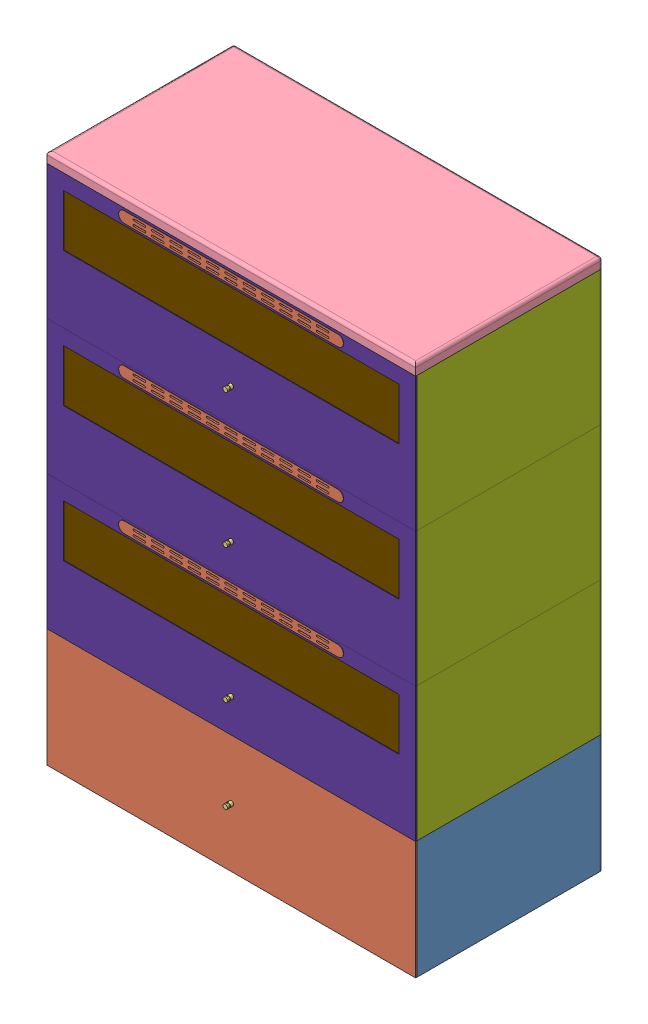
SolidWorks assembly PROTOTIPO2, configuration Default. Lengths in mm.
Overall size (1208 1761 637).
271 component instances, 22 part files, 21 mates.
Components (placement in the parent):
- A_Reservatorio-1: A_Reservatorio [Default] at (-162.7352 -41.8365 75.0131) size (1208 407 632)
  - EstruturaReservatorio-1: EstruturaReservatorio [Default] at (444.341 733.9299 556.3755) size (1208 387 608)
  - PortaReservatorio-1: PortaReservatorio [Default] at (444.341 733.9299 1164.3763) size (1208 387 608)
  - PuxadorGavetaReservatorio-1: PuxadorGavetaReservatorio [Default] at (444.341 733.9299 1188.3763) x (0.021258 -0.999774 0) z (0 0 1) size (15 15 20)
  - ApoioReservatorio-1: ApoioReservatorio [Default] at (948.341 520.4299 1084.3755) x (0.91987 0 -0.392224) z (0.392224 0 0.91987) size (50 20 50)
  - ApoioReservatorio-2: ApoioReservatorio [Default] at (-59.659 520.4299 1084.3755) x (0.91987 0 -0.392224) z (0.392224 0 0.91987) size (50 20 50)
  - ApoioReservatorio-3: ApoioReservatorio [Default] at (948.341 520.4299 636.3755) x (0.91987 0 -0.392224) z (0.392224 0 0.91987) size (50 20 50)
  - ApoioReservatorio-4: ApoioReservatorio [Default] at (-59.659 520.4299 636.3755) x (0.91987 0 -0.392224) z (0.392224 0 0.91987) size (50 20 50)
- EncaixeEntreModulos-1: EncaixeEntreModulos [Default] at (-318.3941 883.5934 1235.3886) size (12 4 12)
- EncaixeEntreModulos-2: EncaixeEntreModulos [Default] at (-318.3941 883.5934 635.3886) x (0 0 1) z (-1 0 0) size (12 4 12)
- EncaixeEntreModulos-3: EncaixeEntreModulos [Default] at (881.6059 883.5934 635.3886) x (-1 0 0) z (0 0 -1) size (12 4 12)
- EncaixeEntreModulos-4: EncaixeEntreModulos [Default] at (881.6059 883.5934 1235.3886) x (0 0 -1) z (1 0 0) size (12 4 12)
- A_Modulo-1: A_Modulo [Default] at (130.4864 669.7553 359.7584) size (1208 450 613)
  - Modulo_Peca1-1: Modulo_Peca1 [Default] at (151.1194 215.8381 575.6302) size (604 440 608)
  - Modulo_Peca2-2: Modulo_Peca2 [Default] at (151.1194 215.8381 575.6302) x (-1 0 0) z (0 0 -1) size (644 440 608)
  - Placas_divisao_modulo-3: Placas_divisao_modulo [Default] at (151.1194 278.8381 575.6302) size (1104 77 504)
  - A_Gaveta-3: A_Gaveta [Default] at (-1.3006 -541.9592 64.8858) size (1104 41 504.01)
    - Estrutura_gaveta-2: Estrutura_gaveta [Default] at (152.42 973.7974 512.7504) size (1104 4 504.01)
    - Copo_cultura-81: Copo_cultura [Default] at (-333.58 977.7974 348.7504) size (108 2 164)
    - Copo_cultura-82: Copo_cultura [Default] at (-225.58 977.7974 348.7504) size (108 2 164)
    - Copo_cultura-83: Copo_cultura [Default] at (-117.58 977.7974 348.7504) size (108 2 164)
    - Copo_cultura-84: Copo_cultura [Default] at (-9.58 977.7974 348.7504) size (108 2 164)
    - Copo_cultura-85: Copo_cultura [Default] at (98.42 977.7974 348.7504) size (108 2 164)
    - Copo_cultura-86: Copo_cultura [Default] at (206.42 977.7974 348.7504) size (108 2 164)
    - Copo_cultura-87: Copo_cultura [Default] at (314.42 977.7974 348.7504) size (108 2 164)
    - Copo_cultura-88: Copo_cultura [Default] at (422.42 977.7974 348.7504) size (108 2 164)
    - Copo_cultura-89: Copo_cultura [Default] at (530.42 977.7974 348.7504) size (108 2 164)
    - Copo_cultura-90: Copo_cultura [Default] at (638.42 977.7974 348.7504) size (108 2 164)
    - Copo_cultura-91: Copo_cultura [Default] at (-333.58 977.7974 512.7504) size (108 2 164)
    - Copo_cultura-92: Copo_cultura [Default] at (-333.58 977.7974 676.7504) size (108 2 164)
    - Copo_cultura-93: Copo_cultura [Default] at (-225.58 977.7974 512.7504) size (108 2 164)
    - Copo_cultura-94: Copo_cultura [Default] at (-225.58 977.7974 676.7504) size (108 2 164)
    - Copo_cultura-95: Copo_cultura [Default] at (-117.58 977.7974 512.7504) size (108 2 164)
    - Copo_cultura-96: Copo_cultura [Default] at (-117.58 977.7974 676.7504) size (108 2 164)
    - Copo_cultura-97: Copo_cultura [Default] at (-9.58 977.7974 512.7504) size (108 2 164)
    - Copo_cultura-98: Copo_cultura [Default] at (-9.58 977.7974 676.7504) size (108 2 164)
    - Copo_cultura-99: Copo_cultura [Default] at (98.42 977.7974 512.7504) size (108 2 164)
    - Copo_cultura-100: Copo_cultura [Default] at (98.42 977.7974 676.7504) size (108 2 164)
    - Copo_cultura-101: Copo_cultura [Default] at (206.42 977.7974 512.7504) size (108 2 164)
    - Copo_cultura-102: Copo_cultura [Default] at (206.42 977.7974 676.7504) size (108 2 164)
    - Copo_cultura-103: Copo_cultura [Default] at (314.42 977.7974 512.7504) size (108 2 164)
    - Copo_cultura-104: Copo_cultura [Default] at (314.42 977.7974 676.7504) size (108 2 164)
    - Copo_cultura-105: Copo_cultura [Default] at (422.42 977.7974 512.7504) size (108 2 164)
    - Copo_cultura-106: Copo_cultura [Default] at (422.42 977.7974 676.7504) size (108 2 164)
    - Copo_cultura-107: Copo_cultura [Default] at (530.42 977.7974 512.7504) size (108 2 164)
    - Copo_cultura-108: Copo_cultura [Default] at (530.42 977.7974 676.7504) size (108 2 164)
    - Copo_cultura-109: Copo_cultura [Default] at (638.42 977.7974 512.7504) size (108 2 164)
    - Copo_cultura-110: Copo_cultura [Default] at (638.42 977.7974 676.7504) size (108 2 164)
    - Capsula_Cultura-1: Capsula_Cultura [Default] at (-333.58 976.7974 676.7504) x (0.947711 0 -0.319129) z (0.319129 0 0.947711) size (44 41 44)
    - Capsula_Cultura-2: Capsula_Cultura [Default] at (-225.58 976.7974 676.7504) x (0.947711 0 -0.319129) z (0.319129 0 0.947711) size (44 41 44)
    - Capsula_Cultura-3: Capsula_Cultura [Default] at (-117.58 976.7974 676.7504) x (0.947711 0 -0.319129) z (0.319129 0 0.947711) size (44 41 44)
    - Capsula_Cultura-4: Capsula_Cultura [Default] at (-9.58 976.7974 676.7504) x (0.947711 0 -0.319129) z (0.319129 0 0.947711) size (44 41 44)
    - Capsula_Cultura-5: Capsula_Cultura [Default] at (98.42 976.7974 676.7504) x (0.947711 0 -0.319129) z (0.319129 0 0.947711) size (44 41 44)
    - Capsula_Cultura-6: Capsula_Cultura [Default] at (206.42 976.7974 676.7504) x (0.947711 0 -0.319129) z (0.319129 0 0.947711) size (44 41 44)
    - Capsula_Cultura-7: Capsula_Cultura [Default] at (314.42 976.7974 676.7504) x (0.947711 0 -0.319129) z (0.319129 0 0.947711) size (44 41 44)
    - Capsula_Cultura-8: Capsula_Cultura [Default] at (422.42 976.7974 676.7504) x (0.947711 0 -0.319129) z (0.319129 0 0.947711) size (44 41 44)
    - Capsula_Cultura-9: Capsula_Cultura [Default] at (530.42 976.7974 676.7504) x (0.947711 0 -0.319129) z (0.319129 0 0.947711) size (44 41 44)
    - Capsula_Cultura-10: Capsula_Cultura [Default] at (638.42 976.7974 676.7504) x (0.947711 0 -0.319129) z (0.319129 0 0.947711) size (44 41 44)
    - Capsula_Cultura-11: Capsula_Cultura [Default] at (-333.58 976.7974 512.7504) x (0.947711 0 -0.319129) z (0.319129 0 0.947711) size (44 41 44)
    - Capsula_Cultura-12: Capsula_Cultura [Default] at (-333.58 976.7974 348.7504) x (0.947711 0 -0.319129) z (0.319129 0 0.947711) size (44 41 44)
    - Capsula_Cultura-13: Capsula_Cultura [Default] at (-225.58 976.7974 512.7504) x (0.947711 0 -0.319129) z (0.319129 0 0.947711) size (44 41 44)
    - Capsula_Cultura-14: Capsula_Cultura [Default] at (-225.58 976.7974 348.7504) x (0.947711 0 -0.319129) z (0.319129 0 0.947711) size (44 41 44)
    - Capsula_Cultura-15: Capsula_Cultura [Default] at (-117.58 976.7974 512.7504) x (0.947711 0 -0.319129) z (0.319129 0 0.947711) size (44 41 44)
    - Capsula_Cultura-16: Capsula_Cultura [Default] at (-117.58 976.7974 348.7504) x (0.947711 0 -0.319129) z (0.319129 0 0.947711) size (44 41 44)
    - Capsula_Cultura-17: Capsula_Cultura [Default] at (-9.58 976.7974 512.7504) x (0.947711 0 -0.319129) z (0.319129 0 0.947711) size (44 41 44)
    - Capsula_Cultura-18: Capsula_Cultura [Default] at (-9.58 976.7974 348.7504) x (0.947711 0 -0.319129) z (0.319129 0 0.947711) size (44 41 44)
    - Capsula_Cultura-19: Capsula_Cultura [Default] at (98.42 976.7974 512.7504) x (0.947711 0 -0.319129) z (0.319129 0 0.947711) size (44 41 44)
    - Capsula_Cultura-20: Capsula_Cultura [Default] at (98.42 976.7974 348.7504) x (0.947711 0 -0.319129) z (0.319129 0 0.947711) size (44 41 44)
    - Capsula_Cultura-21: Capsula_Cultura [Default] at (206.42 976.7974 512.7504) x (0.947711 0 -0.319129) z (0.319129 0 0.947711) size (44 41 44)
    - Capsula_Cultura-22: Capsula_Cultura [Default] at (206.42 976.7974 348.7504) x (0.947711 0 -0.319129) z (0.319129 0 0.947711) size (44 41 44)
    - Capsula_Cultura-23: Capsula_Cultura [Default] at (314.42 976.7974 512.7504) x (0.947711 0 -0.319129) z (0.319129 0 0.947711) size (44 41 44)
    - Capsula_Cultura-24: Capsula_Cultura [Default] at (314.42 976.7974 348.7504) x (0.947711 0 -0.319129) z (0.319129 0 0.947711) size (44 41 44)
    - Capsula_Cultura-25: Capsula_Cultura [Default] at (422.42 976.7974 512.7504) x (0.947711 0 -0.319129) z (0.319129 0 0.947711) size (44 41 44)
    - Capsula_Cultura-26: Capsula_Cultura [Default] at (422.42 976.7974 348.7504) x (0.947711 0 -0.319129) z (0.319129 0 0.947711) size (44 41 44)
    - Capsula_Cultura-27: Capsula_Cultura [Default] at (530.42 976.7974 512.7504) x (0.947711 0 -0.319129) z (0.319129 0 0.947711) size (44 41 44)
    - Capsula_Cultura-28: Capsula_Cultura [Default] at (530.42 976.7974 348.7504) x (0.947711 0 -0.319129) z (0.319129 0 0.947711) size (44 41 44)
    - Capsula_Cultura-29: Capsula_Cultura [Default] at (638.42 976.7974 512.7504) x (0.947711 0 -0.319129) z (0.319129 0 0.947711) size (44 41 44)
    - Capsula_Cultura-30: Capsula_Cultura [Default] at (638.42 976.7974 348.7504) x (0.947711 0 -0.319129) z (0.319129 0 0.947711) size (44 41 44)
  - A_Ventilador-1: A_Ventilador [Default] at (-143.7426 484.8829 374.0047) x (-1 0 0) z (0 0 -1) size (121.7 121.7 59)
    - CasingVentilador-1: CasingVentilador [Default] at (5.1379 70.9552 107.3745) size (120 120 59)
    - LigacaoFan_Casing-1: LigacaoFan_Casing [Default] at (5.1379 70.9552 74.8745) size (96 16 5)
    - Fan-1: Fan [Default] at (5.1379 70.9552 79.8745) x (-0.915029 -0.403389 0) z (0 0 1) size (92.31 92.31 5)
  - Tubo_injeccao_agua-2: Tubo_injeccao_agua [Default] at (643.0083 300.8381 325.6302) size (818.93 24.03 249.8)
  - Tubagem_electricidade-1: Tubagem_electricidade [Default] at (-368.8806 215.8381 298.6302) size (40 450 10)
- A_Modulo-4: A_Modulo [Default] at (130.4864 1109.7553 359.7584) size (1208 450 613)
  - Modulo_Peca1-1: Modulo_Peca1 [Default] at (151.1194 215.8381 575.6302) size (604 440 608)
  - Modulo_Peca2-2: Modulo_Peca2 [Default] at (151.1194 215.8381 575.6302) x (-1 0 0) z (0 0 -1) size (644 440 608)
  - Placas_divisao_modulo-3: Placas_divisao_modulo [Default] at (151.1194 278.8381 575.6302) size (1104 77 504)
  - A_Gaveta-3: A_Gaveta [Default] at (-1.3006 -541.9592 64.8858) size (1104 41 504.01)
    - Estrutura_gaveta-2: Estrutura_gaveta [Default] at (152.42 973.7974 512.7504) size (1104 4 504.01)
    - Copo_cultura-81: Copo_cultura [Default] at (-333.58 977.7974 348.7504) size (108 2 164)
    - Copo_cultura-82: Copo_cultura [Default] at (-225.58 977.7974 348.7504) size (108 2 164)
    - Copo_cultura-83: Copo_cultura [Default] at (-117.58 977.7974 348.7504) size (108 2 164)
    - Copo_cultura-84: Copo_cultura [Default] at (-9.58 977.7974 348.7504) size (108 2 164)
    - Copo_cultura-85: Copo_cultura [Default] at (98.42 977.7974 348.7504) size (108 2 164)
    - Copo_cultura-86: Copo_cultura [Default] at (206.42 977.7974 348.7504) size (108 2 164)
    - Copo_cultura-87: Copo_cultura [Default] at (314.42 977.7974 348.7504) size (108 2 164)
    - Copo_cultura-88: Copo_cultura [Default] at (422.42 977.7974 348.7504) size (108 2 164)
    - Copo_cultura-89: Copo_cultura [Default] at (530.42 977.7974 348.7504) size (108 2 164)
    - Copo_cultura-90: Copo_cultura [Default] at (638.42 977.7974 348.7504) size (108 2 164)
    - Copo_cultura-91: Copo_cultura [Default] at (-333.58 977.7974 512.7504) size (108 2 164)
    - Copo_cultura-92: Copo_cultura [Default] at (-333.58 977.7974 676.7504) size (108 2 164)
    - Copo_cultura-93: Copo_cultura [Default] at (-225.58 977.7974 512.7504) size (108 2 164)
    - Copo_cultura-94: Copo_cultura [Default] at (-225.58 977.7974 676.7504) size (108 2 164)
    - Copo_cultura-95: Copo_cultura [Default] at (-117.58 977.7974 512.7504) size (108 2 164)
    - Copo_cultura-96: Copo_cultura [Default] at (-117.58 977.7974 676.7504) size (108 2 164)
    - Copo_cultura-97: Copo_cultura [Default] at (-9.58 977.7974 512.7504) size (108 2 164)
    - Copo_cultura-98: Copo_cultura [Default] at (-9.58 977.7974 676.7504) size (108 2 164)
    - Copo_cultura-99: Copo_cultura [Default] at (98.42 977.7974 512.7504) size (108 2 164)
    - Copo_cultura-100: Copo_cultura [Default] at (98.42 977.7974 676.7504) size (108 2 164)
    - Copo_cultura-101: Copo_cultura [Default] at (206.42 977.7974 512.7504) size (108 2 164)
    - Copo_cultura-102: Copo_cultura [Default] at (206.42 977.7974 676.7504) size (108 2 164)
    - Copo_cultura-103: Copo_cultura [Default] at (314.42 977.7974 512.7504) size (108 2 164)
    - Copo_cultura-104: Copo_cultura [Default] at (314.42 977.7974 676.7504) size (108 2 164)
    - Copo_cultura-105: Copo_cultura [Default] at (422.42 977.7974 512.7504) size (108 2 164)
    - Copo_cultura-106: Copo_cultura [Default] at (422.42 977.7974 676.7504) size (108 2 164)
    - Copo_cultura-107: Copo_cultura [Default] at (530.42 977.7974 512.7504) size (108 2 164)
    - Copo_cultura-108: Copo_cultura [Default] at (530.42 977.7974 676.7504) size (108 2 164)
    - Copo_cultura-109: Copo_cultura [Default] at (638.42 977.7974 512.7504) size (108 2 164)
    - Copo_cultura-110: Copo_cultura [Default] at (638.42 977.7974 676.7504) size (108 2 164)
    - Capsula_Cultura-1: Capsula_Cultura [Default] at (-333.58 976.7974 676.7504) x (0.947711 0 -0.319129) z (0.319129 0 0.947711) size (44 41 44)
    - Capsula_Cultura-2: Capsula_Cultura [Default] at (-225.58 976.7974 676.7504) x (0.947711 0 -0.319129) z (0.319129 0 0.947711) size (44 41 44)
    - Capsula_Cultura-3: Capsula_Cultura [Default] at (-117.58 976.7974 676.7504) x (0.947711 0 -0.319129) z (0.319129 0 0.947711) size (44 41 44)
    - Capsula_Cultura-4: Capsula_Cultura [Default] at (-9.58 976.7974 676.7504) x (0.947711 0 -0.319129) z (0.319129 0 0.947711) size (44 41 44)
    - Capsula_Cultura-5: Capsula_Cultura [Default] at (98.42 976.7974 676.7504) x (0.947711 0 -0.319129) z (0.319129 0 0.947711) size (44 41 44)
    - Capsula_Cultura-6: Capsula_Cultura [Default] at (206.42 976.7974 676.7504) x (0.947711 0 -0.319129) z (0.319129 0 0.947711) size (44 41 44)
    - Capsula_Cultura-7: Capsula_Cultura [Default] at (314.42 976.7974 676.7504) x (0.947711 0 -0.319129) z (0.319129 0 0.947711) size (44 41 44)
    - Capsula_Cultura-8: Capsula_Cultura [Default] at (422.42 976.7974 676.7504) x (0.947711 0 -0.319129) z (0.319129 0 0.947711) size (44 41 44)
    - Capsula_Cultura-9: Capsula_Cultura [Default] at (530.42 976.7974 676.7504) x (0.947711 0 -0.319129) z (0.319129 0 0.947711) size (44 41 44)
    - Capsula_Cultura-10: Capsula_Cultura [Default] at (638.42 976.7974 676.7504) x (0.947711 0 -0.319129) z (0.319129 0 0.947711) size (44 41 44)
    - Capsula_Cultura-11: Capsula_Cultura [Default] at (-333.58 976.7974 512.7504) x (0.947711 0 -0.319129) z (0.319129 0 0.947711) size (44 41 44)
    - Capsula_Cultura-12: Capsula_Cultura [Default] at (-333.58 976.7974 348.7504) x (0.947711 0 -0.319129) z (0.319129 0 0.947711) size (44 41 44)
    - Capsula_Cultura-13: Capsula_Cultura [Default] at (-225.58 976.7974 512.7504) x (0.947711 0 -0.319129) z (0.319129 0 0.947711) size (44 41 44)
    - Capsula_Cultura-14: Capsula_Cultura [Default] at (-225.58 976.7974 348.7504) x (0.947711 0 -0.319129) z (0.319129 0 0.947711) size (44 41 44)
    - Capsula_Cultura-15: Capsula_Cultura [Default] at (-117.58 976.7974 512.7504) x (0.947711 0 -0.319129) z (0.319129 0 0.947711) size (44 41 44)
    - Capsula_Cultura-16: Capsula_Cultura [Default] at (-117.58 976.7974 348.7504) x (0.947711 0 -0.319129) z (0.319129 0 0.947711) size (44 41 44)
    - Capsula_Cultura-17: Capsula_Cultura [Default] at (-9.58 976.7974 512.7504) x (0.947711 0 -0.319129) z (0.319129 0 0.947711) size (44 41 44)
    - Capsula_Cultura-18: Capsula_Cultura [Default] at (-9.58 976.7974 348.7504) x (0.947711 0 -0.319129) z (0.319129 0 0.947711) size (44 41 44)
    - Capsula_Cultura-19: Capsula_Cultura [Default] at (98.42 976.7974 512.7504) x (0.947711 0 -0.319129) z (0.319129 0 0.947711) size (44 41 44)
    - Capsula_Cultura-20: Capsula_Cultura [Default] at (98.42 976.7974 348.7504) x (0.947711 0 -0.319129) z (0.319129 0 0.947711) size (44 41 44)
    - Capsula_Cultura-21: Capsula_Cultura [Default] at (206.42 976.7974 512.7504) x (0.947711 0 -0.319129) z (0.319129 0 0.947711) size (44 41 44)
    - Capsula_Cultura-22: Capsula_Cultura [Default] at (206.42 976.7974 348.7504) x (0.947711 0 -0.319129) z (0.319129 0 0.947711) size (44 41 44)
    - Capsula_Cultura-23: Capsula_Cultura [Default] at (314.42 976.7974 512.7504) x (0.947711 0 -0.319129) z (0.319129 0 0.947711) size (44 41 44)
    - Capsula_Cultura-24: Capsula_Cultura [Default] at (314.42 976.7974 348.7504) x (0.947711 0 -0.319129) z (0.319129 0 0.947711) size (44 41 44)
    - Capsula_Cultura-25: Capsula_Cultura [Default] at (422.42 976.7974 512.7504) x (0.947711 0 -0.319129) z (0.319129 0 0.947711) size (44 41 44)
    - Capsula_Cultura-26: Capsula_Cultura [Default] at (422.42 976.7974 348.7504) x (0.947711 0 -0.319129) z (0.319129 0 0.947711) size (44 41 44)
    - Capsula_Cultura-27: Capsula_Cultura [Default] at (530.42 976.7974 512.7504) x (0.947711 0 -0.319129) z (0.319129 0 0.947711) size (44 41 44)
    - Capsula_Cultura-28: Capsula_Cultura [Default] at (530.42 976.7974 348.7504) x (0.947711 0 -0.319129) z (0.319129 0 0.947711) size (44 41 44)
    - Capsula_Cultura-29: Capsula_Cultura [Default] at (638.42 976.7974 512.7504) x (0.947711 0 -0.319129) z (0.319129 0 0.947711) size (44 41 44)
    - Capsula_Cultura-30: Capsula_Cultura [Default] at (638.42 976.7974 348.7504) x (0.947711 0 -0.319129) z (0.319129 0 0.947711) size (44 41 44)
  - A_Ventilador-1: A_Ventilador [Default] at (-143.7426 484.8829 374.0047) x (-1 0 0) z (0 0 -1) size (121.7 121.7 59)
    - CasingVentilador-1: CasingVentilador [Default] at (5.1379 70.9552 107.3745) size (120 120 59)
    - LigacaoFan_Casing-1: LigacaoFan_Casing [Default] at (5.1379 70.9552 74.8745) size (96 16 5)
    - Fan-1: Fan [Default] at (5.1379 70.9552 79.8745) x (-0.915029 -0.403389 0) z (0 0 1) size (92.31 92.31 5)
  - Tubo_injeccao_agua-2: Tubo_injeccao_agua [Default] at (643.0083 300.8381 325.6302) size (818.93 24.03 249.8)
  - Tubagem_electricidade-1: Tubagem_electricidade [Default] at (-368.8806 215.8381 298.6302) size (40 450 10)
- A_Modulo-5: A_Modulo [Default] at (130.4864 1549.7553 359.7584) size (1208 450 613)
  - Modulo_Peca1-1: Modulo_Peca1 [Default] at (151.1194 215.8381 575.6302) size (604 440 608)
  - Modulo_Peca2-2: Modulo_Peca2 [Default] at (151.1194 215.8381 575.6302) x (-1 0 0) z (0 0 -1) size (644 440 608)
  - Placas_divisao_modulo-3: Placas_divisao_modulo [Default] at (151.1194 278.8381 575.6302) size (1104 77 504)
  - A_Gaveta-3: A_Gaveta [Default] at (-1.3006 -541.9592 64.8858) size (1104 41 504.01)
    - Estrutura_gaveta-2: Estrutura_gaveta [Default] at (152.42 973.7974 512.7504) size (1104 4 504.01)
    - Copo_cultura-81: Copo_cultura [Default] at (-333.58 977.7974 348.7504) size (108 2 164)
    - Copo_cultura-82: Copo_cultura [Default] at (-225.58 977.7974 348.7504) size (108 2 164)
    - Copo_cultura-83: Copo_cultura [Default] at (-117.58 977.7974 348.7504) size (108 2 164)
    - Copo_cultura-84: Copo_cultura [Default] at (-9.58 977.7974 348.7504) size (108 2 164)
    - Copo_cultura-85: Copo_cultura [Default] at (98.42 977.7974 348.7504) size (108 2 164)
    - Copo_cultura-86: Copo_cultura [Default] at (206.42 977.7974 348.7504) size (108 2 164)
    - Copo_cultura-87: Copo_cultura [Default] at (314.42 977.7974 348.7504) size (108 2 164)
    - Copo_cultura-88: Copo_cultura [Default] at (422.42 977.7974 348.7504) size (108 2 164)
    - Copo_cultura-89: Copo_cultura [Default] at (530.42 977.7974 348.7504) size (108 2 164)
    - Copo_cultura-90: Copo_cultura [Default] at (638.42 977.7974 348.7504) size (108 2 164)
    - Copo_cultura-91: Copo_cultura [Default] at (-333.58 977.7974 512.7504) size (108 2 164)
    - Copo_cultura-92: Copo_cultura [Default] at (-333.58 977.7974 676.7504) size (108 2 164)
    - Copo_cultura-93: Copo_cultura [Default] at (-225.58 977.7974 512.7504) size (108 2 164)
    - Copo_cultura-94: Copo_cultura [Default] at (-225.58 977.7974 676.7504) size (108 2 164)
    - Copo_cultura-95: Copo_cultura [Default] at (-117.58 977.7974 512.7504) size (108 2 164)
    - Copo_cultura-96: Copo_cultura [Default] at (-117.58 977.7974 676.7504) size (108 2 164)
    - Copo_cultura-97: Copo_cultura [Default] at (-9.58 977.7974 512.7504) size (108 2 164)
    - Copo_cultura-98: Copo_cultura [Default] at (-9.58 977.7974 676.7504) size (108 2 164)
    - Copo_cultura-99: Copo_cultura [Default] at (98.42 977.7974 512.7504) size (108 2 164)
    - Copo_cultura-100: Copo_cultura [Default] at (98.42 977.7974 676.7504) size (108 2 164)
    - Copo_cultura-101: Copo_cultura [Default] at (206.42 977.7974 512.7504) size (108 2 164)
    - Copo_cultura-102: Copo_cultura [Default] at (206.42 977.7974 676.7504) size (108 2 164)
    - Copo_cultura-103: Copo_cultura [Default] at (314.42 977.7974 512.7504) size (108 2 164)
    - Copo_cultura-104: Copo_cultura [Default] at (314.42 977.7974 676.7504) size (108 2 164)
    - Copo_cultura-105: Copo_cultura [Default] at (422.42 977.7974 512.7504) size (108 2 164)
    - Copo_cultura-106: Copo_cultura [Default] at (422.42 977.7974 676.7504) size (108 2 164)
    - Copo_cultura-107: Copo_cultura [Default] at (530.42 977.7974 512.7504) size (108 2 164)
    - Copo_cultura-108: Copo_cultura [Default] at (530.42 977.7974 676.7504) size (108 2 164)
    - Copo_cultura-109: Copo_cultura [Default] at (638.42 977.7974 512.7504) size (108 2 164)
    - Copo_cultura-110: Copo_cultura [Default] at (638.42 977.7974 676.7504) size (108 2 164)
    - Capsula_Cultura-1: Capsula_Cultura [Default] at (-333.58 976.7974 676.7504) x (0.947711 0 -0.319129) z (0.319129 0 0.947711) size (44 41 44)
    - Capsula_Cultura-2: Capsula_Cultura [Default] at (-225.58 976.7974 676.7504) x (0.947711 0 -0.319129) z (0.319129 0 0.947711) size (44 41 44)
    - Capsula_Cultura-3: Capsula_Cultura [Default] at (-117.58 976.7974 676.7504) x (0.947711 0 -0.319129) z (0.319129 0 0.947711) size (44 41 44)
    - Capsula_Cultura-4: Capsula_Cultura [Default] at (-9.58 976.7974 676.7504) x (0.947711 0 -0.319129) z (0.319129 0 0.947711) size (44 41 44)
    - Capsula_Cultura-5: Capsula_Cultura [Default] at (98.42 976.7974 676.7504) x (0.947711 0 -0.319129) z (0.319129 0 0.947711) size (44 41 44)
    - Capsula_Cultura-6: Capsula_Cultura [Default] at (206.42 976.7974 676.7504) x (0.947711 0 -0.319129) z (0.319129 0 0.947711) size (44 41 44)
    - Capsula_Cultura-7: Capsula_Cultura [Default] at (314.42 976.7974 676.7504) x (0.947711 0 -0.319129) z (0.319129 0 0.947711) size (44 41 44)
    - Capsula_Cultura-8: Capsula_Cultura [Default] at (422.42 976.7974 676.7504) x (0.947711 0 -0.319129) z (0.319129 0 0.947711) size (44 41 44)
    - Capsula_Cultura-9: Capsula_Cultura [Default] at (530.42 976.7974 676.7504) x (0.947711 0 -0.319129) z (0.319129 0 0.947711) size (44 41 44)
    - Capsula_Cultura-10: Capsula_Cultura [Default] at (638.42 976.7974 676.7504) x (0.947711 0 -0.319129) z (0.319129 0 0.947711) size (44 41 44)
    - Capsula_Cultura-11: Capsula_Cultura [Default] at (-333.58 976.7974 512.7504) x (0.947711 0 -0.319129) z (0.319129 0 0.947711) size (44 41 44)
    - Capsula_Cultura-12: Capsula_Cultura [Default] at (-333.58 976.7974 348.7504) x (0.947711 0 -0.319129) z (0.319129 0 0.947711) size (44 41 44)
    - Capsula_Cultura-13: Capsula_Cultura [Default] at (-225.58 976.7974 512.7504) x (0.947711 0 -0.319129) z (0.319129 0 0.947711) size (44 41 44)
    - Capsula_Cultura-14: Capsula_Cultura [Default] at (-225.58 976.7974 348.7504) x (0.947711 0 -0.319129) z (0.319129 0 0.947711) size (44 41 44)
    - Capsula_Cultura-15: Capsula_Cultura [Default] at (-117.58 976.7974 512.7504) x (0.947711 0 -0.319129) z (0.319129 0 0.947711) size (44 41 44)
    - Capsula_Cultura-16: Capsula_Cultura [Default] at (-117.58 976.7974 348.7504) x (0.947711 0 -0.319129) z (0.319129 0 0.947711) size (44 41 44)
    - Capsula_Cultura-17: Capsula_Cultura [Default] at (-9.58 976.7974 512.7504) x (0.947711 0 -0.319129) z (0.319129 0 0.947711) size (44 41 44)
    - Capsula_Cultura-18: Capsula_Cultura [Default] at (-9.58 976.7974 348.7504) x (0.947711 0 -0.319129) z (0.319129 0 0.947711) size (44 41 44)
    - Capsula_Cultura-19: Capsula_Cultura [Default] at (98.42 976.7974 512.7504) x (0.947711 0 -0.319129) z (0.319129 0 0.947711) size (44 41 44)
    - Capsula_Cultura-20: Capsula_Cultura [Default] at (98.42 976.7974 348.7504) x (0.947711 0 -0.319129) z (0.319129 0 0.947711) size (44 41 44)
    - Capsula_Cultura-21: Capsula_Cultura [Default] at (206.42 976.7974 512.7504) x (0.947711 0 -0.319129) z (0.319129 0 0.947711) size (44 41 44)
    - Capsula_Cultura-22: Capsula_Cultura [Default] at (206.42 976.7974 348.7504) x (0.947711 0 -0.319129) z (0.319129 0 0.947711) size (44 41 44)
    - Capsula_Cultura-23: Capsula_Cultura [Default] at (314.42 976.7974 512.7504) x (0.947711 0 -0.319129) z (0.319129 0 0.947711) size (44 41 44)
    - Capsula_Cultura-24: Capsula_Cultura [Default] at (314.42 976.7974 348.7504) x (0.947711 0 -0.319129) z (0.319129 0 0.947711) size (44 41 44)
    - Capsula_Cultura-25: Capsula_Cultura [Default] at (422.42 976.7974 512.7504) x (0.947711 0 -0.319129) z (0.319129 0 0.947711) size (44 41 44)
    - Capsula_Cultura-26: Capsula_Cultura [Default] at (422.42 976.7974 348.7504) x (0.947711 0 -0.319129) z (0.319129 0 0.947711) size (44 41 44)
    - Capsula_Cultura-27: Capsula_Cultura [Default] at (530.42 976.7974 512.7504) x (0.947711 0 -0.319129) z (0.319129 0 0.947711) size (44 41 44)
    - Capsula_Cultura-28: Capsula_Cultura [Default] at (530.42 976.7974 348.7504) x (0.947711 0 -0.319129) z (0.319129 0 0.947711) size (44 41 44)
    - Capsula_Cultura-29: Capsula_Cultura [Default] at (638.42 976.7974 512.7504) x (0.947711 0 -0.319129) z (0.319129 0 0.947711) size (44 41 44)
    - Capsula_Cultura-30: Capsula_Cultura [Default] at (638.42 976.7974 348.7504) x (0.947711 0 -0.319129) z (0.319129 0 0.947711) size (44 41 44)
  - A_Ventilador-1: A_Ventilador [Default] at (-143.7426 484.8829 374.0047) x (-1 0 0) z (0 0 -1) size (121.7 121.7 59)
    - CasingVentilador-1: CasingVentilador [Default] at (5.1379 70.9552 107.3745) size (120 120 59)
    - LigacaoFan_Casing-1: LigacaoFan_Casing [Default] at (5.1379 70.9552 74.8745) size (96 16 5)
    - Fan-1: Fan [Default] at (5.1379 70.9552 79.8745) x (-0.915029 -0.403389 0) z (0 0 1) size (92.31 92.31 5)
  - Tubo_injeccao_agua-2: Tubo_injeccao_agua [Default] at (643.0083 300.8381 325.6302) size (818.93 24.03 249.8)
  - Tubagem_electricidade-1: Tubagem_electricidade [Default] at (-368.8806 215.8381 298.6302) size (40 450 10)
- EncaixeEntreModulos-17: EncaixeEntreModulos [Default] at (881.6059 1323.5934 1235.3886) x (0 0 -1) z (1 0 0) size (12 4 12)
- EncaixeEntreModulos-18: EncaixeEntreModulos [Default] at (881.6059 1763.5934 1235.3886) x (0 0 -1) z (1 0 0) size (12 4 12)
- EncaixeEntreModulos-19: EncaixeEntreModulos [Default] at (881.6059 2203.5934 1235.3886) x (0 0 -1) z (1 0 0) size (12 4 12)
- EncaixeEntreModulos-20: EncaixeEntreModulos [Default] at (881.6059 1323.5934 635.3886) x (-1 0 0) z (0 0 -1) size (12 4 12)
- EncaixeEntreModulos-21: EncaixeEntreModulos [Default] at (881.6059 1763.5934 635.3886) x (-1 0 0) z (0 0 -1) size (12 4 12)
- EncaixeEntreModulos-22: EncaixeEntreModulos [Default] at (881.6059 2203.5934 635.3886) x (-1 0 0) z (0 0 -1) size (12 4 12)
- EncaixeEntreModulos-23: EncaixeEntreModulos [Default] at (-318.3941 1323.5934 635.3886) x (0 0 1) z (-1 0 0) size (12 4 12)
- EncaixeEntreModulos-24: EncaixeEntreModulos [Default] at (-318.3941 1763.5934 635.3886) x (0 0 1) z (-1 0 0) size (12 4 12)
- EncaixeEntreModulos-25: EncaixeEntreModulos [Default] at (-318.3941 2203.5934 635.3886) x (0 0 1) z (-1 0 0) size (12 4 12)
- EncaixeEntreModulos-26: EncaixeEntreModulos [Default] at (-318.3941 1323.5934 1235.3886) size (12 4 12)
- EncaixeEntreModulos-27: EncaixeEntreModulos [Default] at (-318.3941 1763.5934 1235.3886) size (12 4 12)
- EncaixeEntreModulos-28: EncaixeEntreModulos [Default] at (-318.3941 2203.5934 1235.3886) size (12 4 12)
- A_PortaModulo-4: A_PortaModulo [Default] at (-761.505 1230.0596 642.3583) x (-1 0 0) z (0 0 -1) size (1208 440 24)
  - Porta_estrutura-1: Porta_estrutura [Default] at (-1043.1108 -124.4662 -601.0303) size (1208 440 4)
  - Vidro_porta-1: Vidro_porta [Default] at (-1043.1108 -39.4662 -599.0303) size (1120 180 1)
  - Encaixe_moldura_vidro-1: Encaixe_moldura_vidro [Default] at (-1043.1108 -39.4662 -597.0303) x (-1 0 0) z (0 0 -1) size (1120 180 3)
  - GrelhaRespiracao-1: GrelhaRespiracao [Default] at (-1043.1108 70.5338 -602.0303) size (736 36 5)
  - Puxador_porta_modulo-1: Puxador_porta_modulo [Default] at (-1043.1108 -234.4662 -621.0303) x (-0.416199 0.909274 0) z (0 0 -1) size (15 15 20)
- A_PortaModulo-5: A_PortaModulo [Default] at (-761.505 1670.0596 642.3583) x (-1 0 0) z (0 0 -1) size (1208 440 24)
  - Porta_estrutura-1: Porta_estrutura [Default] at (-1043.1108 -124.4662 -601.0303) size (1208 440 4)
  - Vidro_porta-1: Vidro_porta [Default] at (-1043.1108 -39.4662 -599.0303) size (1120 180 1)
  - Encaixe_moldura_vidro-1: Encaixe_moldura_vidro [Default] at (-1043.1108 -39.4662 -597.0303) x (-1 0 0) z (0 0 -1) size (1120 180 3)
  - GrelhaRespiracao-1: GrelhaRespiracao [Default] at (-1043.1108 70.5338 -602.0303) size (736 36 5)
  - Puxador_porta_modulo-1: Puxador_porta_modulo [Default] at (-1043.1108 -234.4662 -621.0303) x (-0.416199 0.909274 0) z (0 0 -1) size (15 15 20)
- A_PortaModulo-6: A_PortaModulo [Default] at (-761.505 2110.0596 642.3583) x (-1 0 0) z (0 0 -1) size (1208 440 24)
  - Porta_estrutura-1: Porta_estrutura [Default] at (-1043.1108 -124.4662 -601.0303) size (1208 440 4)
  - Vidro_porta-1: Vidro_porta [Default] at (-1043.1108 -39.4662 -599.0303) size (1120 180 1)
  - Encaixe_moldura_vidro-1: Encaixe_moldura_vidro [Default] at (-1043.1108 -39.4662 -597.0303) x (-1 0 0) z (0 0 -1) size (1120 180 3)
  - GrelhaRespiracao-1: GrelhaRespiracao [Default] at (-1043.1108 70.5338 -602.0303) size (736 36 5)
  - Puxador_porta_modulo-1: Puxador_porta_modulo [Default] at (-1043.1108 -234.4662 -621.0303) x (-0.416199 0.909274 0) z (0 0 -1) size (15 15 20)
- Tampa-2: Tampa [Default] at (281.6059 2239.5934 937.3886) x (1 0 0) z (0 0 -1) size (1208 34 612)
- A_Ventilador-1: A_Ventilador [Default] at (-13.2562 2034.6382 737.7631) x (-1 0 0) z (0 0 -1) size (121.7 121.7 59)
  - CasingVentilador-1: CasingVentilador [Default] at (5.1379 70.9552 107.3745) size (120 120 59)
  - LigacaoFan_Casing-1: LigacaoFan_Casing [Default] at (5.1379 70.9552 74.8745) size (96 16 5)
  - Fan-1: Fan [Default] at (5.1379 70.9552 79.8745) x (-0.915029 -0.403389 0) z (0 0 1) size (92.31 92.31 5)
- A_Ventilador-2: A_Ventilador [Default] at (-13.2562 1594.6382 737.7631) x (-1 0 0) z (0 0 -1) size (121.7 121.7 59)
  - CasingVentilador-1: CasingVentilador [Default] at (5.1379 70.9552 107.3745) size (120 120 59)
  - LigacaoFan_Casing-1: LigacaoFan_Casing [Default] at (5.1379 70.9552 74.8745) size (96 16 5)
  - Fan-1: Fan [Default] at (5.1379 70.9552 79.8745) x (-0.915029 -0.403389 0) z (0 0 1) size (92.31 92.31 5)
- A_Ventilador-3: A_Ventilador [Default] at (-13.2562 1154.6382 737.7631) x (-1 0 0) z (0 0 -1) size (121.7 121.7 59)
  - CasingVentilador-1: CasingVentilador [Default] at (5.1379 70.9552 107.3745) size (120 120 59)
  - LigacaoFan_Casing-1: LigacaoFan_Casing [Default] at (5.1379 70.9552 74.8745) size (96 16 5)
  - Fan-1: Fan [Default] at (5.1379 70.9552 79.8745) x (-0.915029 -0.403389 0) z (0 0 1) size (92.31 92.31 5)
Mates (geometry in assembly coordinates):
- Coincident1: coincident: line of A_Reservatorio-1/EstruturaReservatorio-1 through (-316.3941 883.5934 1233.3886) axis (0 0 -1); line of EncaixeEntreModulos-1 through (-316.3941 883.5934 1233.3886) axis (0 0 -1)
- Coincident2: coincident: line of A_Reservatorio-1/EstruturaReservatorio-1 through (-318.3941 883.5934 1235.3886) axis (1 0 0); line of EncaixeEntreModulos-1 through (-317.3941 883.5934 1235.3886) axis (1 0 0)
- Coincident3: coincident: line of A_Reservatorio-1/EstruturaReservatorio-1 through (-306.3941 883.5934 637.3886) axis (-1 0 0); line of EncaixeEntreModulos-2 through (-316.3941 883.5934 637.3886) axis (1 0 0)
- Coincident4: coincident: line of A_Reservatorio-1/EstruturaReservatorio-1 through (-318.3941 883.5934 647.3886) axis (0 0 -1); line of EncaixeEntreModulos-2 through (-318.3941 883.5934 636.3886) axis (0 0 1)
- Coincident12: coincident: point of A_Reservatorio-1/EstruturaReservatorio-1; point of EncaixeEntreModulos-3
- Coincident13: coincident: point of A_Reservatorio-1/EstruturaReservatorio-1; point of EncaixeEntreModulos-3
- Coincident14: coincident: line of A_Reservatorio-1/EstruturaReservatorio-1 through (881.6059 883.5934 635.3886) axis (-1 0 0); point of EncaixeEntreModulos-3
- Coincident15: coincident: point of A_Reservatorio-1/EstruturaReservatorio-1; point of EncaixeEntreModulos-4
- Coincident16: coincident: point of A_Reservatorio-1/EstruturaReservatorio-1; point of EncaixeEntreModulos-4
- Coincident17: coincident: line of A_Reservatorio-1/EstruturaReservatorio-1 through (881.6059 883.5934 1235.3886) axis (-1 0 0); line of EncaixeEntreModulos-4 through (869.6059 883.5934 1235.3886) axis (1 0 0)
- Coincident18: coincident: line of EncaixeEntreModulos-4 through (869.6059 887.5934 1233.3886) axis (0 0 1); line of A_Modulo-1/Modulo_Peca2-2 through (869.6059 887.5934 1235.3886) axis (0 0 -1)
- Coincident19: coincident: point of EncaixeEntreModulos-4; point of A_Modulo-1/Modulo_Peca2-2
- Coincident20: coincident: line of A_Modulo-1/Modulo_Peca1-1 through (-322.3941 1325.5934 1239.3886) axis (0 -1 0); line of A_PortaModulo-4/Porta_estrutura-1 through (-322.3941 885.5934 1239.3886) axis (0 1 0)
- Coincident22: coincident: line of A_Modulo-1/Modulo_Peca2-2 through (885.6059 1325.5934 1239.3886) axis (0 -1 0); line of A_PortaModulo-4/Porta_estrutura-1 through (885.6059 1325.5934 1239.3886) axis (0 -1 0)
- Coincident23: coincident: plane of A_Reservatorio-1/PortaReservatorio-1 through (-322.3941 885.5934 1243.3894) normal (0 1 0); line of A_PortaModulo-4/Porta_estrutura-1 through (885.6059 885.5934 1243.3886) axis (-1 0 0)
- Coincident24: coincident: line of A_Modulo-5/Modulo_Peca2-2 through (877.6059 2205.5934 631.3886) axis (-1 0 0); line of Tampa-2 through (-314.3941 2205.5934 631.3886) axis (1 0 0)
- Coincident25: coincident: line of A_PortaModulo-6/Porta_estrutura-1 through (-322.3941 2205.5934 1243.3886) axis (1 0 0); line of Tampa-2 through (885.6059 2205.5934 1243.3886) axis (-1 0 0)
- Coincident26: coincident: line of A_Modulo-5/Modulo_Peca2-2 through (885.6059 2205.5934 1239.3886) axis (0 0 -1); line of Tampa-2 through (885.6059 2205.5934 639.3886) axis (0 0 1)
- Coincident28: coincident: line of A_Modulo-5/Modulo_Peca1-1 through (-68.3941 2062.5934 631.3886) axis (0 1 0); line of A_Ventilador-1/CasingVentilador-1 through (-68.3941 2059.5934 631.3886) axis (0 1 0)
- Coincident29: coincident: line of A_Modulo-5/Modulo_Peca1-1 through (31.6059 2062.5934 631.3886) axis (0 1 0); line of A_Ventilador-1/CasingVentilador-1 through (31.6059 2059.5934 631.3886) axis (0 1 0)
- Coincident30: coincident: plane of A_Modulo-5/Modulo_Peca1-1 through (-68.3941 2055.5934 631.3886) normal (0 1 0); plane of A_Ventilador-1/CasingVentilador-1 through (31.6059 2055.5934 689.3886) normal (0 -1 0)
